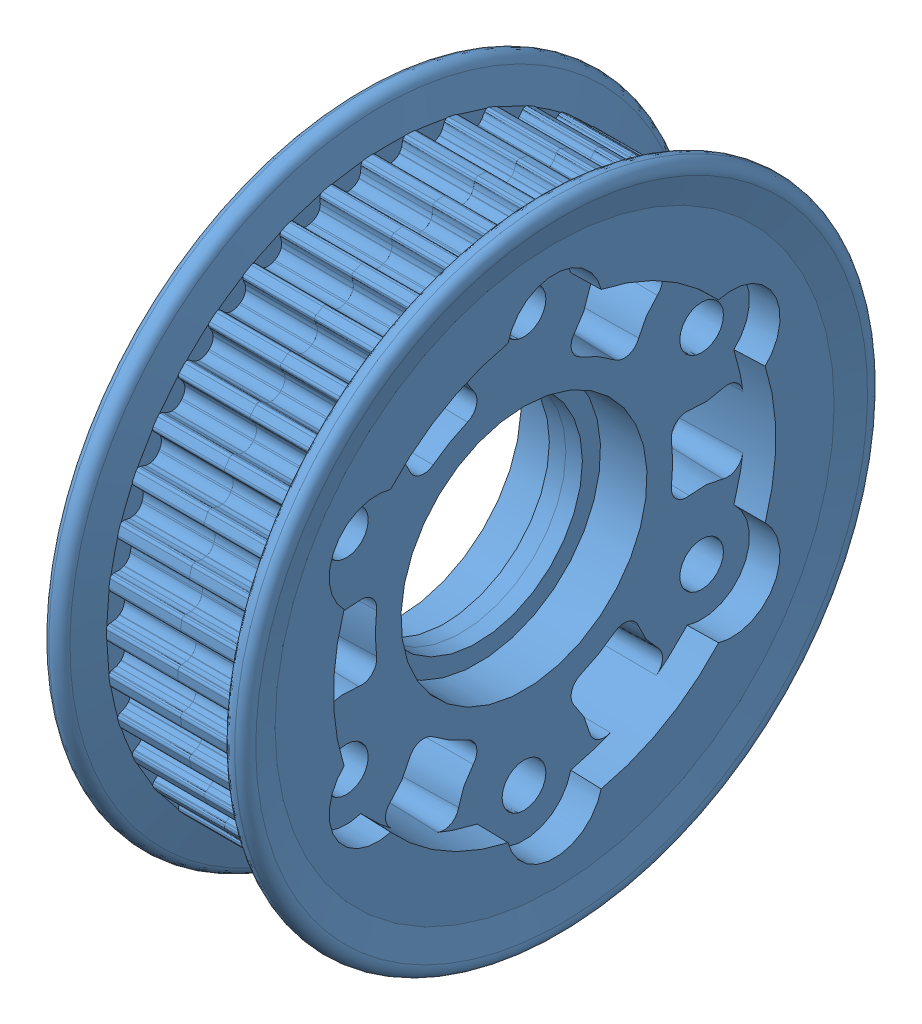
SolidWorks assembly 42 - 2014 tooth pulley assembly, configuration Default. Lengths in mm.
Overall size (23.46 74.23 74.23).
2 component instances, 1 part files, 4 mates.
Components (placement in the parent):
- 42 tooth HTD Pulley half 2014-1: 42 tooth HTD Pulley half 2014 [Default] at origin size (13 74.23 74.23)
- 42 tooth HTD Pulley half 2014-2: 42 tooth HTD Pulley half 2014 [Default] at (16.6624 0 0) x (-1 0 0) z (0 0.000084 1) size (13 74.23 74.23)
Mates (geometry in assembly coordinates):
- Concentric15: concentric anti-aligned: cylinder of 42 tooth HTD Pulley half 2014-1 through (8.3312 -23.8125 0.002) axis (-1 0 0) radius 2.54; cylinder of 42 tooth HTD Pulley half 2014-2 through (8.3312 -23.8125 0.002) axis (1 0 0) radius 2.54
- Concentric16: concentric anti-aligned: cylinder of 42 tooth HTD Pulley half 2014-1 through (8.3312 23.8125 0) axis (-1 0 0) radius 2.54; cylinder of 42 tooth HTD Pulley half 2014-2 through (8.3312 23.8125 0) axis (1 0 0) radius 2.54
- Coincident22: coincident anti-aligned: plane of 42 tooth HTD Pulley half 2014-1 through (8.3312 32.198 0.1238) normal (1 0 0); plane of 42 tooth HTD Pulley half 2014-2 through (8.3312 -32.198 0.1265) normal (-1 0 0)
- Coincident23: coordinate: point of 42 tooth HTD Pulley half 2014-1; point of assembly
